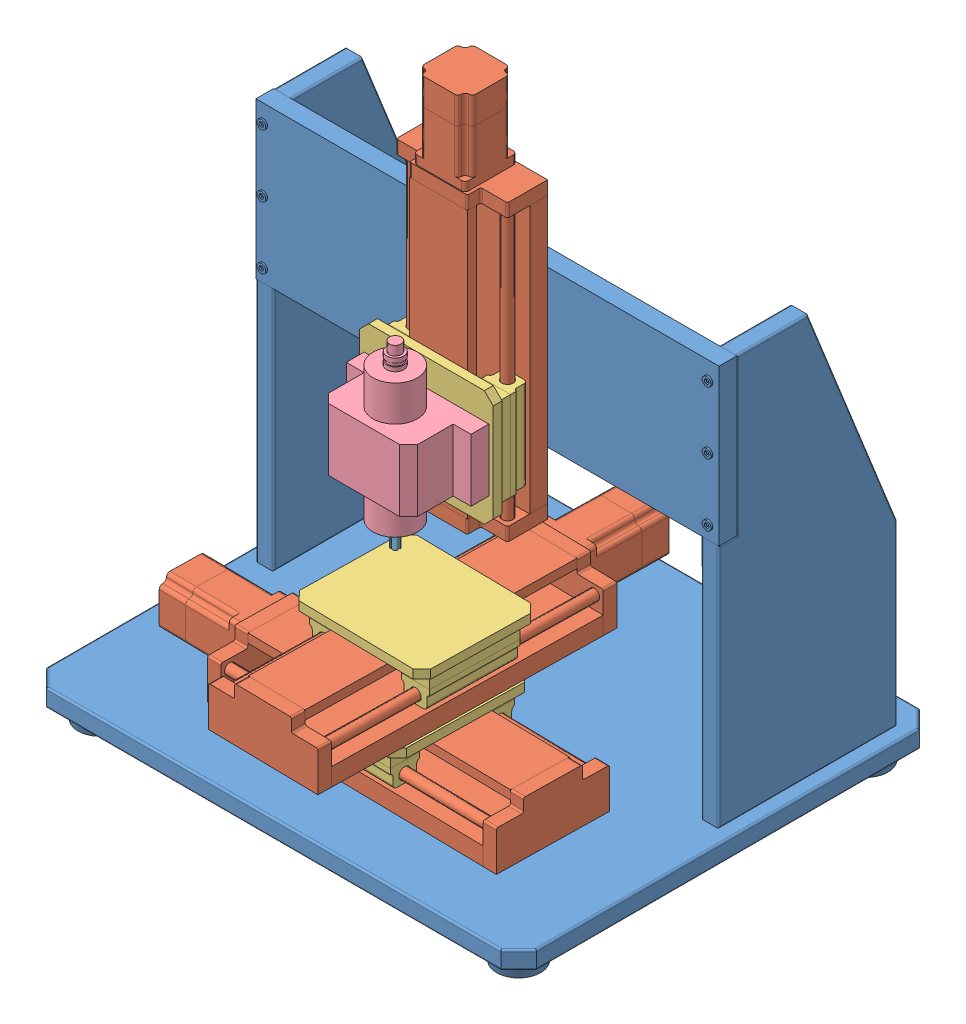
SolidWorks assembly assem, configuration Default. Lengths in mm.
Overall size (550 665 495.54).
9 component instances, 5 part files, 16 mates.
Components (placement in the parent):
- CAD-1: CAD [Default] at origin size (550 490 470)
- CAD2-1: CAD2 [Default] at (15.3617 20.0051 98.8689) x (-0.999848 0 -0.017452) z (0.017452 0 -0.999848) size (420 60 125)
- table-1: table [Default] at (15.3767 55.0051 98.8692) x (-0.017452 0 0.999848) z (-0.999848 0 -0.017452) size (150 48 130)
- CAD2-2: CAD2 [Default] at (15.4535 93.5051 94.4697) x (0.017452 0 -0.999848) z (0.999848 0 0.017452) size (420 60 125)
- table-2: table [Default] at (15.4969 128.5051 91.985) x (0.999848 0 0.017452) z (-0.017452 0 0.999848) size (150 48 130)
- CAD2-3: CAD2 [Default] at (5 390 -5) x (0 1 0) z (1 0 0) size (420 60 125)
- spindle-1: spindle [Default] at (5 287.99 68.5) size (140 186.18 70)
- table-3: table [Default] at (5 322.99 30) x (1 0 0) z (0 -1 0) size (150 48 130)
- spindle2-1: spindle2 [Default] at (5 220.5721 103.5) size (8.53 15 8.53)
Mates (geometry in assembly coordinates):
- Concentric1: concentric aligned: cylinder of CAD2-1 through (-152.4996 55.0051 148.4469) axis (0.999848 0 0.017452) radius 6; cylinder of table-1 through (-35.5319 55.0051 150.4886) axis (0.999848 0 0.017452) radius 6.5
- Concentric3: concentric aligned: cylinder of CAD2-1 through (-150.6671 55.0051 43.4629) axis (0.999848 0 0.017452) radius 6; cylinder of table-1 through (-33.6994 55.0051 45.5046) axis (0.999848 0 0.017452) radius 6.5
- Coincident1: coincident anti-aligned: plane of table-1 through (15.3767 93.5051 98.8692) normal (0 1 0); plane of CAD2-2 through (15.4535 93.5051 94.4697) normal (0 -1 0)
- Distance1: distance = 2.5 mm aligned: plane of CAD2-2 through (-49.6548 113.5051 243.356) normal (-0.999848 0 -0.017452); plane of table-1 through (-48.3044 93.5051 22.7462) normal (-0.999848 0 -0.017452)
- Concentric4: concentric anti-aligned: cylinder of CAD2-2 through (-34.1244 128.5051 -73.3917) axis (-0.017452 0 0.999848) radius 6; cylinder of table-2 through (-37.8677 128.5051 141.0612) axis (0.017452 0 -0.999848) radius 6.5
- Concentric5: concentric anti-aligned: cylinder of CAD2-2 through (70.8596 128.5051 -71.5592) axis (-0.017452 0 0.999848) radius 6; cylinder of table-2 through (67.1163 128.5051 142.8937) axis (0.017452 0 -0.999848) radius 6.5
- Coincident3: coincident anti-aligned: plane of CAD-1 through (0 0 -5) normal (0 0 1); plane of CAD2-3 through (5 390 -5) normal (0 0 -1)
- Distance2: distance = 70 mm aligned: plane of CAD2-3 through (5 225 -5) normal (0 -1 0); plane of CAD-1 through (-260 295 -5) normal (0 -1 0)
- Distance3: distance = 202.5 mm aligned: plane of CAD2-3 through (-57.5 240 15) normal (-1 0 0); plane of CAD-1 through (-260 470 -205) normal (-1 0 0)
- Concentric6: concentric anti-aligned: cylinder of CAD2-3 through (57.5 556.9706 30) axis (0 -1 0) radius 6; cylinder of table-3 through (57.5 272.99 30) axis (0 1 0) radius 6.5
- Concentric7: concentric anti-aligned: cylinder of CAD2-3 through (-47.5 556.9706 30) axis (0 -1 0) radius 6; cylinder of table-3 through (-47.5 272.99 30) axis (0 1 0) radius 6.5
- Coincident7: coincident anti-aligned: plane of spindle-1 through (75 357.99 68.5) normal (0 0 -1); plane of table-3 through (5 322.99 68.5) normal (0 0 1)
- Distance4: distance = 5 mm: plane of spindle-1 through (75 357.99 68.5) normal (1 0 0); line of table-3 through (80 267.99 68.5) axis (0 1 0)
- Distance5: distance = 30 mm aligned: plane of spindle-1 through (5 357.99 68.5) normal (0 1 0); plane of table-3 through (-70 387.99 68.5) normal (0 1 0)
- Coincident10: coincident anti-aligned: plane of spindle-1 through (5 235.5721 103.5) normal (0 -1 0); plane of spindle2-1 through (5 235.5721 103.5) normal (0 1 0)
- Concentric9: concentric anti-aligned: cylinder of spindle-1 through (5 247.99 103.5) axis (0 1 0) radius 4.8915; cylinder of spindle2-1 through (5 235.5721 103.5) axis (0 -1 0) radius 4.5
